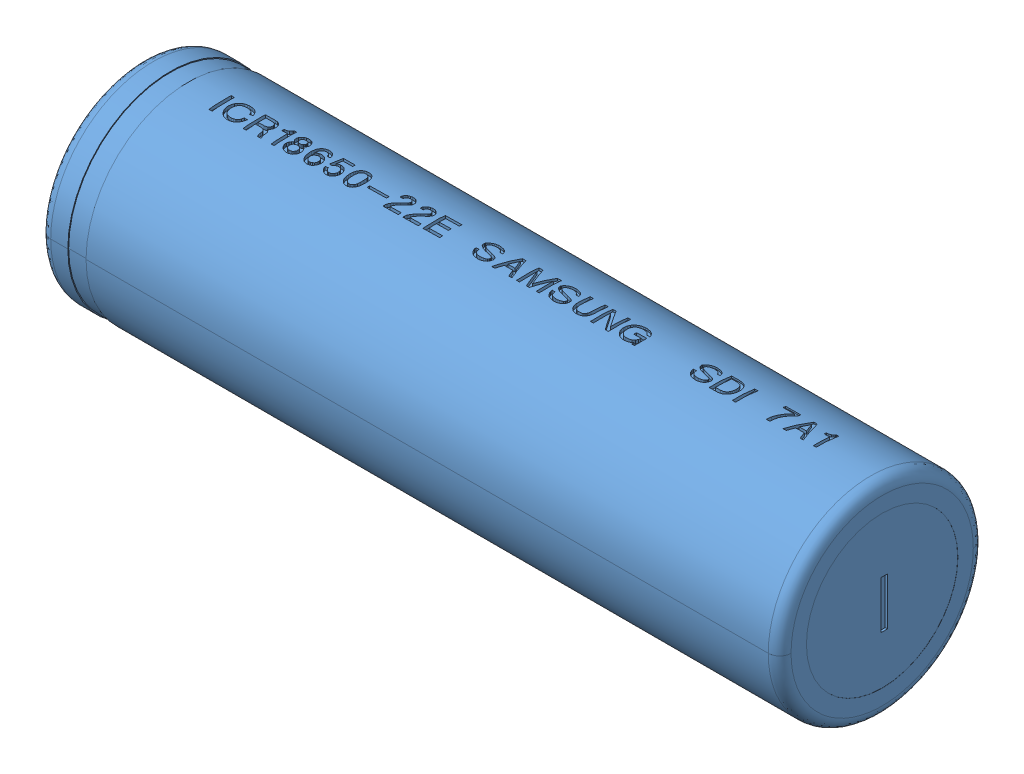
SolidWorks assembly Battery Samsung ICR 18650 -22E, configuration Default. Lengths in mm.
Overall size (65 18 18).
2 component instances, 1 part files, 0 mates.
Components (placement in the parent):
- Battery Samsung ICR 18650 -22E.stp-1: Battery Samsung ICR 18650 -22E.stp [Default] at origin size (65 18 18)
  - Samsung_ICR18650-22E.stp-1: Samsung_ICR18650-22E.stp [Default] at (-2.1716 -9.5821 -7.9726) x (0 0 -1) z (1 0 0) size (18 18 65)
